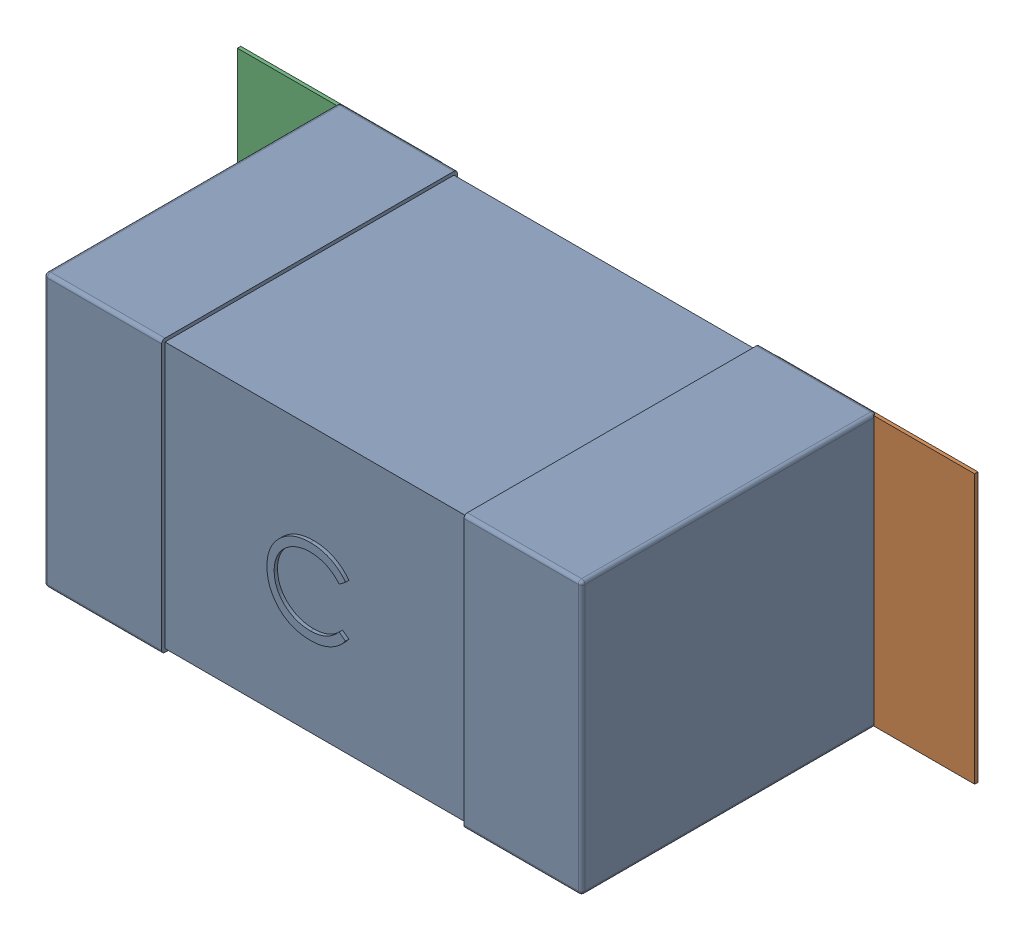
SolidWorks assembly C33, configuration Défaut. Lengths in mm.
Overall size (2.19 0.81 0.88).
5 component instances, 2 part files, 0 mates.
Components (placement in the parent):
- 0603_C-1: 0603_C [Défaut] at (8.9379 -10.3602 0) x (1 0 0) z (0 0 1) size (1.6 0.81 0.88)
- 6634915696-1: 6634915696 [Défaut] at (10.1879 -10.3602 0) size (0.6 0.8 0.01)
  - Extruded_497-1: Extruded_497 [Défaut] at origin size (0.6 0.8 0.01)
- 6634915696-2: 6634915696 [Défaut] at (8.593 -10.3602 0) size (0.6 0.8 0.01)
  - Extruded_497-1: Extruded_497 [Défaut] at origin size (0.6 0.8 0.01)
